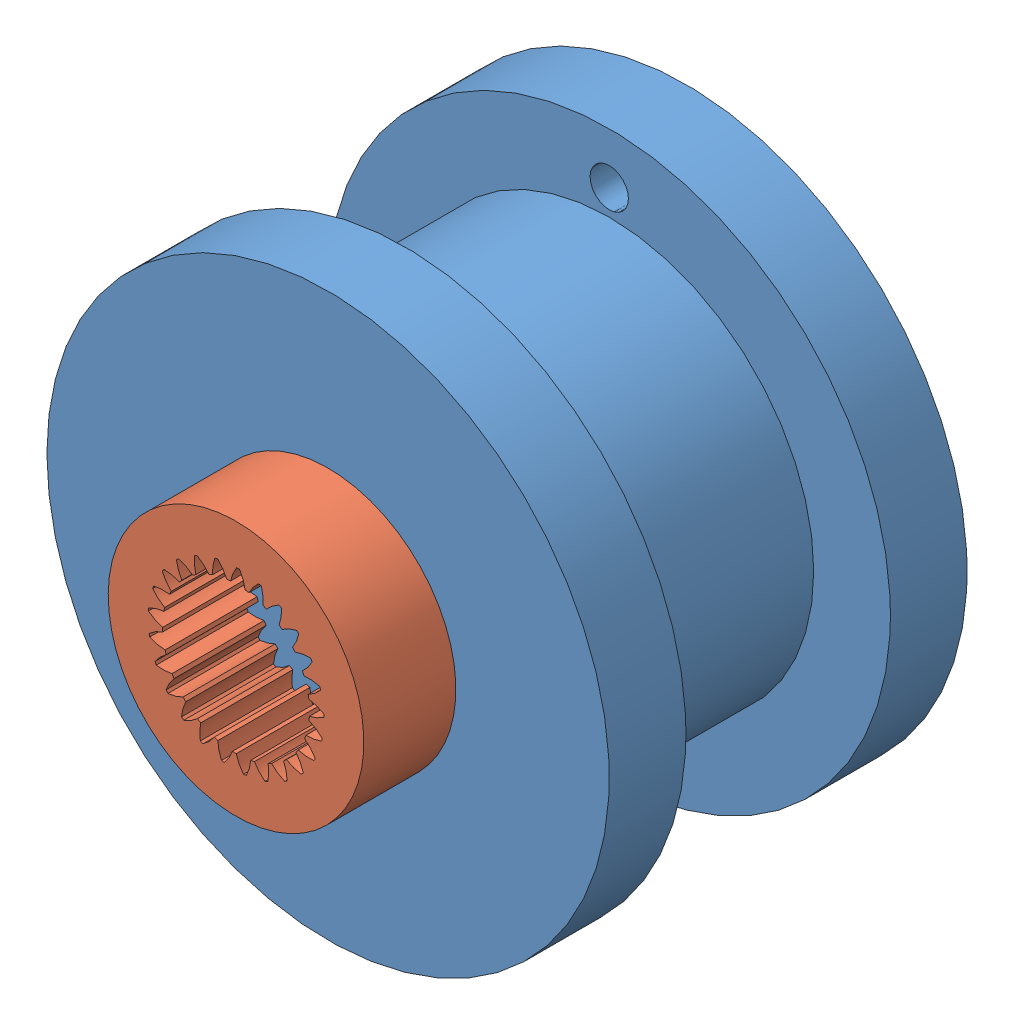
SolidWorks assembly pully16, configuration Default. Lengths in mm.
Overall size (22 22 17.6).
2 component instances, 2 part files, 2 mates.
Components (placement in the parent):
- pully15_1-1: pully15_1 [Default] at (4.2601 1.1139 -19.6512) size (22 22 14)
- internal spur gear_iso-3: internal spur gear_iso [ISO - Internal spur gear 0.25M 25T 14.5PA 3.6FW ---S25S10OD 1.0AF] at (4.2601 1.1139 -5.6512) x (0 0 1) z (-0.974391 -0.224858 0) size (3.6 10 10)
Mates (geometry in assembly coordinates):
- Concentric3: concentric anti-aligned: cylinder of pully15_1-1 through (4.2601 1.1139 -19.6512) axis (0 0 1) radius 1.55; cylinder of internal spur gear_iso-3 through (4.2601 1.1139 -15.6512) axis (0 0 -1) radius 5
- Coincident2: coincident anti-aligned: plane of pully15_1-1 through (4.2601 1.1139 -5.6512) normal (0 0 1); plane of internal spur gear_iso-3 through (7.0615 1.7603 -5.6512) normal (0 0 -1)
